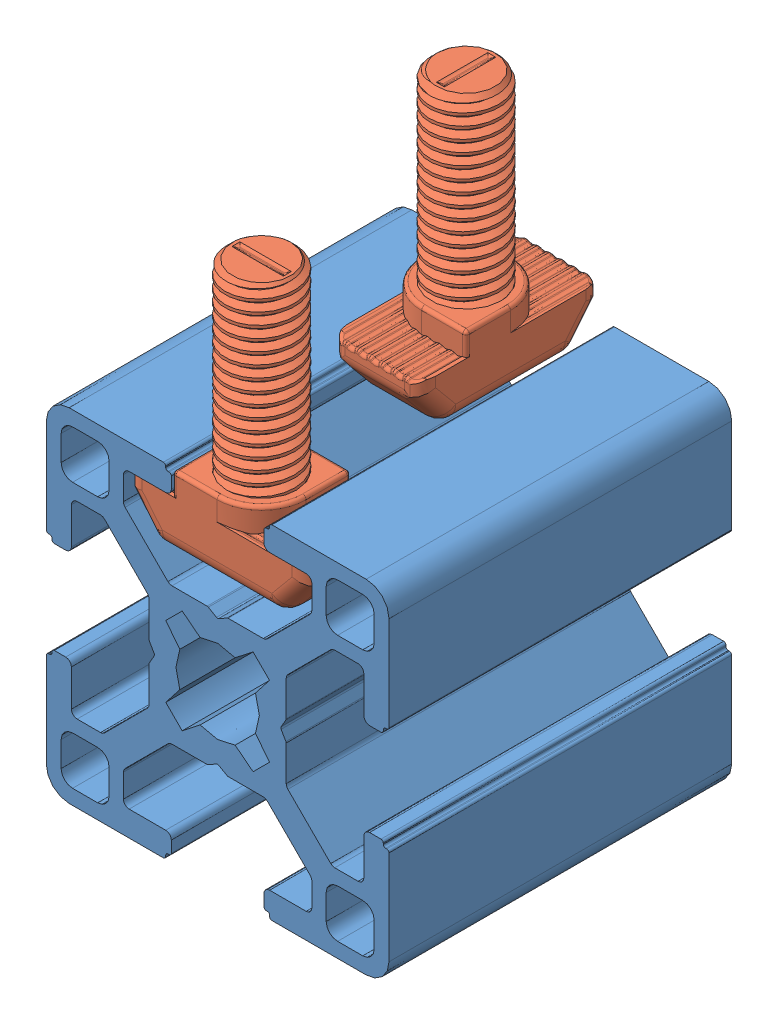
SolidWorks assembly Сборка Т-Болт 8 паз, configuration По умолчанию. Lengths in mm.
Overall size (30 51.61 30).
3 component instances, 2 part files, 5 mates.
Components (placement in the parent):
- 30х30-1: 30х30 [По умолчанию] at origin size (30 30 30)
- Т-Болт 8 паз-1: Т-Болт 8 паз [По умолчанию] at (-0.05 8.3 26.1) size (16.08 22.91 7.8)
- Т-Болт 8 паз-2: Т-Болт 8 паз [По умолчанию] at (-0.05 13.6975 8.2024) x (0 0 -1) z (1 0 0) size (16.08 22.91 7.8)
Mates (geometry in assembly coordinates):
- Совпадение1: coincident anti-aligned: plane of 30х30-1 through (0 12.8 30) normal (0 -1 0); plane of Т-Гайка 8 паз-1 through (7.95 12.8 22.2) normal (0 1 0)
- Совпадение2: coincident aligned: plane of 30х30-1 through (0 0 30) normal (0 0 1); plane of Т-Гайка 8 паз-1 through (-0.05 8.3 30) normal (0 0 1)
- Совпадение3: coincident aligned: plane of Т-Гайка 8 паз-1 through (3.85 12.8 22.2) normal (1 0 0); plane of Т-Гайка 8 паз-2 through (3.85 13.6975 8.2024) normal (1 0 0)
- Параллельность1: parallel anti-aligned: plane of 30х30-1 through (0 15 30) normal (0 1 0); plane of Т-Гайка 8 паз-2 through (-3.95 13.6975 2.7024) normal (0 -1 0)
- Расстояние1: distance = 0.1 mm anti-aligned: plane of 30х30-1 through (-4.05 0 30) normal (1 0 0); plane of Т-Гайка 8 паз-1 through (-3.95 12.8 22.2) normal (-1 0 0)
